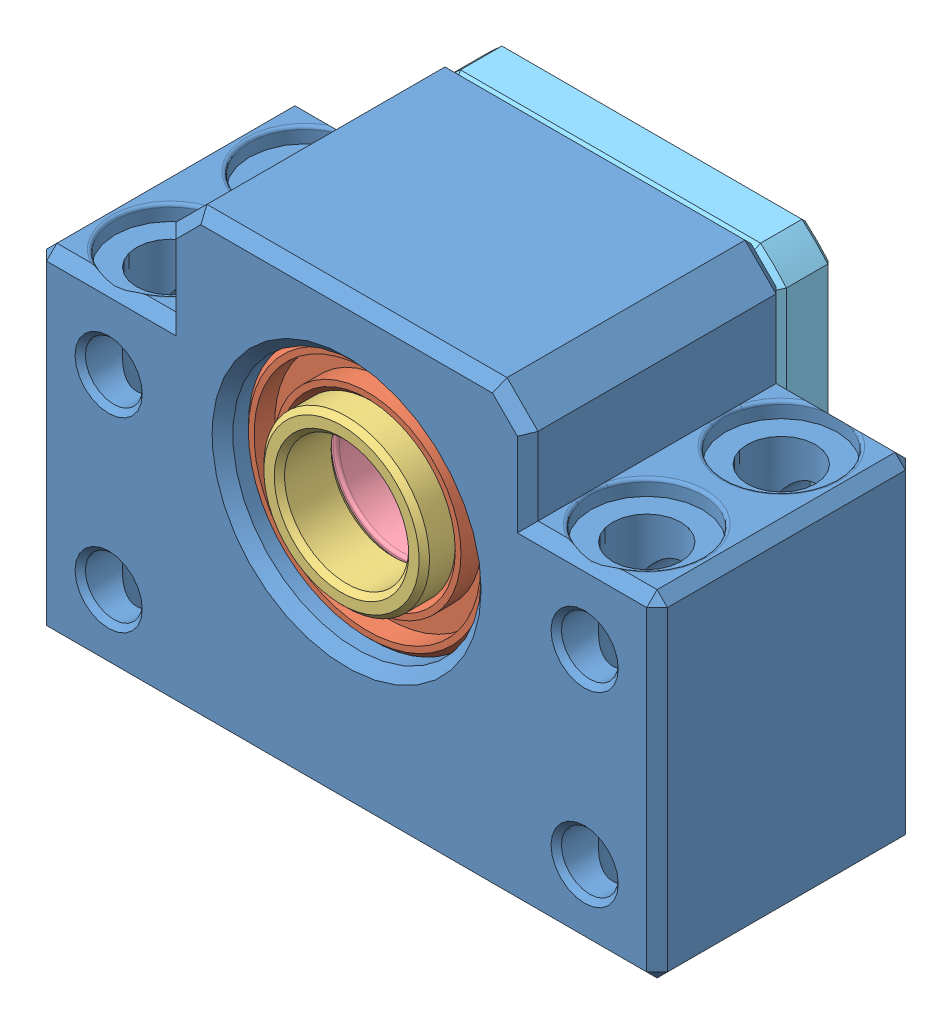
SolidWorks assembly BK12, configuration Default. Lengths in mm.
Overall size (60 43 35.16).
9 component instances, 6 part files, 18 mates.
Components (placement in the parent):
- BK12-1-1: BK12-1 [Default] at (-11.028 26.197 -11.9785) size (60 43 25)
- BK12-2-5: BK12-2 [Default] at (-11.028 8.197 8.0215) size (24 24 3)
- BK12-3-4: BK12-3 [Default] at (-11.028 8.197 8.0215) size (16 16 5.5)
- 6001-Bearing-3: 6001-Bearing [Default] at (-11.028 8.197 0.0215) size (28 28 8)
- 6001-Bearing-4: 6001-Bearing [Default] at (-11.028 8.197 -7.9785) size (28 28 8)
- BK12-2-6: BK12-2 [Default] at (-11.028 8.197 -7.9785) x (-1 0 0) z (0 0 -1) size (24 24 3)
- BK12-3-5: BK12-3 [Default] at (-11.028 8.197 -13.4785) size (16 16 5.5)
- BK12-4-1: BK12-4 [Default] at (-11.028 8.197 -16.9785) size (34 34 9)
- BK12-5-1: BK12-5 [Default] at (-11.028 8.197 -21.4785) size (19 19 8.53)
Mates (geometry in assembly coordinates):
- Concentric12: concentric aligned: cylinder of BK12-2-5 through (-11.028 8.197 11.0215) axis (0 0 -1) radius 8; cylinder of BK12-3-4 through (-11.028 8.197 13.5215) axis (0 0 -1) radius 8
- Coincident10: coincident aligned: plane of BK12-2-5 through (-11.028 8.197 8.0215) normal (0 0 -1); plane of BK12-3-4 through (-11.028 8.197 8.0215) normal (0 0 -1)
- Concentric13: concentric aligned: cylinder of BK12-1-1 through (-11.028 8.197 13.0215) axis (0 0 -1) radius 12; cylinder of BK12-2-5 through (-11.028 8.197 11.0215) axis (0 0 -1) radius 12
- Coincident11: coincident aligned: plane of BK12-1-1 through (-11.028 8.197 8.0215) normal (0 0 -1); plane of BK12-2-5 through (-11.028 8.197 8.0215) normal (0 0 -1)
- Concentric14: concentric aligned: cylinder of BK12-1-1 through (-11.028 8.197 8.0215) axis (0 0 -1) radius 14; cylinder of 6001-Bearing-3 through (-11.028 8.197 8.0215) axis (0 0 -1) radius 14
- Coincident12: coincident anti-aligned: plane of BK12-1-1 through (-11.028 8.197 8.0215) normal (0 0 -1); plane of 6001-Bearing-3 through (-11.028 8.197 8.0215) normal (0 0 1)
- Concentric15: concentric aligned: cylinder of BK12-1-1 through (-11.028 8.197 8.0215) axis (0 0 -1) radius 14; cylinder of 6001-Bearing-4 through (-11.028 8.197 0.0215) axis (0 0 -1) radius 14
- Coincident13: coincident anti-aligned: plane of 6001-Bearing-3 through (-11.028 8.197 0.0215) normal (0 0 -1); plane of 6001-Bearing-4 through (-11.028 8.197 0.0215) normal (0 0 1)
- Concentric16: concentric anti-aligned: cylinder of BK12-2-6 through (-11.028 8.197 -10.9785) axis (0 0 1) radius 8; cylinder of BK12-3-5 through (-11.028 8.197 -7.9785) axis (0 0 -1) radius 8
- Coincident14: coincident aligned: plane of BK12-2-6 through (-11.028 8.197 -7.9785) normal (0 0 1); plane of BK12-3-5 through (-11.028 8.197 -7.9785) normal (0 0 1)
- Concentric17: concentric anti-aligned: cylinder of BK12-1-1 through (-11.028 8.197 8.0215) axis (0 0 -1) radius 14; cylinder of BK12-2-6 through (-11.028 8.197 -10.9785) axis (0 0 1) radius 12
- Coincident15: coincident anti-aligned: plane of 6001-Bearing-4 through (-11.028 8.197 -7.9785) normal (0 0 -1); plane of BK12-2-6 through (-11.028 8.197 -7.9785) normal (0 0 1)
- Concentric18: concentric anti-aligned: cylinder of BK12-1-1 through (-11.028 8.197 8.0215) axis (0 0 -1) radius 14; cylinder of BK12-4-1 through (-11.028 8.197 -11.9785) axis (0 0 1) radius 14
- Angle1: planar angle = 0 rad aligned: plane of BK12-4-1 through (-25.528 25.197 -7.9785) normal (0 1 0); plane of BK12-1-1 through (6.472 26.197 13.0215) normal (0 1 0)
- Coincident17: coincident anti-aligned: plane of BK12-1-1 through (18.972 -16.803 -11.9785) normal (0 0 -1); plane of BK12-4-1 through (-11.028 8.197 -11.9785) normal (0 0 1)
- Coincident22: coincident anti-aligned: plane of BK12-3-5 through (-11.028 8.197 -13.4785) normal (0 0 -1); plane of BK12-5-1 through (-11.028 8.197 -13.4785) normal (0 0 1)
- Concentric23: concentric anti-aligned: circle of BK12-3-5; circle of BK12-5-1
- Angle2: planar angle = 0 rad aligned: plane of BK12-5-1 through (-16.428 17.697 -13.4785) normal (0 1 0); plane of BK12-4-1 through (-25.528 25.197 -7.9785) normal (0 1 0)
